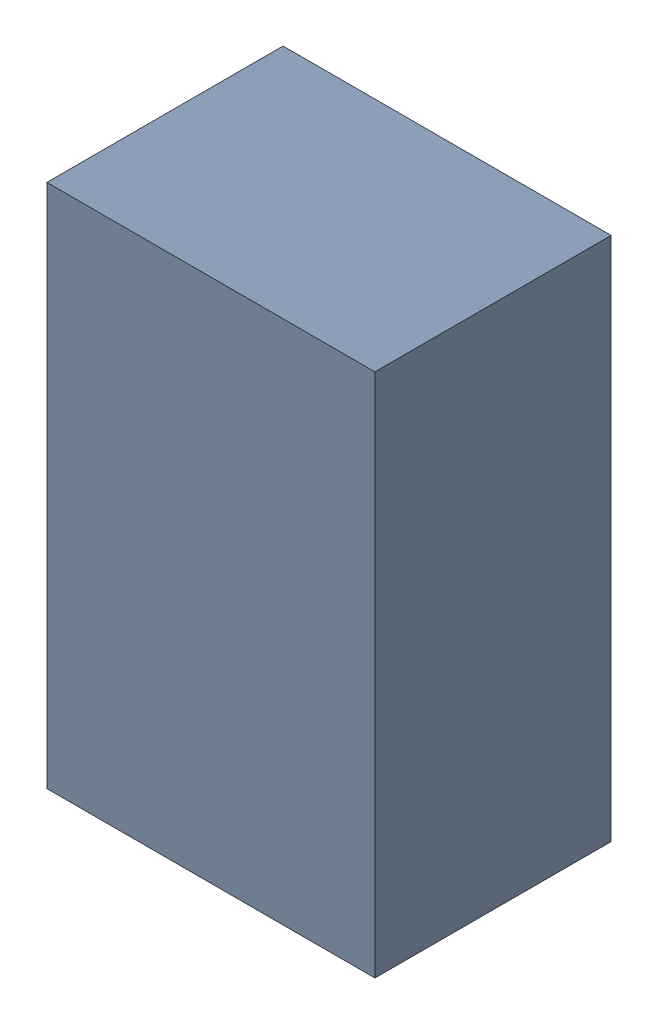
SolidWorks assembly U8, configuration Default. Lengths in mm.
Overall size (1.25 2 0.9).
2 component instances, 1 part files, 0 mates.
Components (placement in the parent):
- 870945920-1: 870945920 [Default] at (17.6522 30.9566 -2.6006) size (1.25 2 0.9)
  - Extruded_8-1: Extruded_8 [Default] at origin size (1.25 2 0.9)
